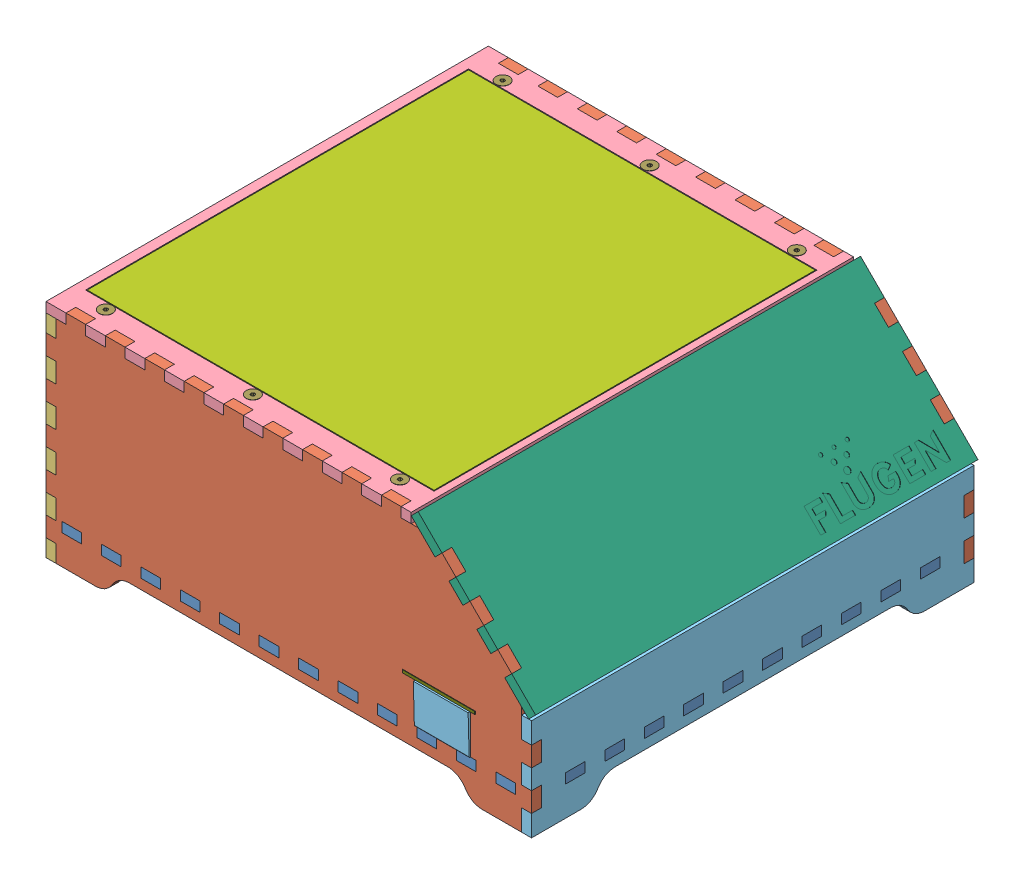
SolidWorks assembly Box assembly R3, configuration Default. Lengths in mm.
Overall size (283.8 130.94 257.74).
91 component instances, 32 part files, 72 mates.
Components (placement in the parent):
- Base 1.3-1: Base 1.3 [Default] at (-719.69 -41.4282 -151.4157) x (1 0 0) z (0 -1 0) size (281.43 256.43 5.71)
- Side panel 1.3-1: Side panel 1.3 [Default] at (-151.1145 -87.4893 122.5004) size (281.43 128.58 5.71)
- Side panel 1.3-2: Side panel 1.3 [Default] at (-151.116 -87.4893 -128.2154) size (281.43 128.58 5.71)
- Backplate 1.3-1: Backplate 1.3 [Default] at (-134.9997 1297.1843 -151.4157) x (0 -1 0) z (-1 0 0) size (122.86 256.43 5.72)
- Top 1.3-1: Top 1.3 [Default] at (1095.0385 64.2887 151.4157) x (-1 0 0) z (0 -1 0) size (211.67 256.43 5.71)
- Front-1: Front [Default] at (140.7147 -927.5509 151.4157) x (0 1 0) z (-1 0 0) size (58.82 256.43 5.71)
- Panel 1.3-1: Panel 1.3 [Default] at (-579.0317 720.6839 -151.4157) x (0.707107 -0.707107 0) z (-0.707107 -0.707107 0) size (96.28 256.43 5.71)
- Peltier assembly-1: Peltier assembly [Default] at (-209.5588 163.9846 -91.398) x (0 0 1) z (1 0 0) size (238 60.94 201)
  - Cold plate-1: Cold plate [Default] at (91.398 99.6959 175.559) size (221 3 201)
  - Heatsink-1: Heatsink [Default] at (31.898 106.6959 75.309) size (119 27.24 200.5)
  - Heatsink-2: Heatsink [Default] at (150.898 106.6959 75.309) size (119 27.24 200.5)
  - 92mm Fan Guard-1: 92mm Fan Guard [Default] at (32.0916 156.652 125.8154) x (0.999999 0 0.001368) z (-0.001368 0 0.999999) size (90.49 4.78 90.49)
  - F9-1: F9 [Default] at (64.0963 125.1552 120.7546) size (93.27 26.59 93.52)
    - F9.STEP-1: F9.STEP [Default] at origin size (93.27 26.59 93.52)
      - F9 body.STEP-1: F9 body.STEP [Default] at (-78.1983 5.7094 50.7544) size (92.01 26.59 92.01)
      - F9 fan.STEP-1: F9 fan.STEP [Default] at (-74.2115 10.4094 -44.9134) x (-0.083202 0 0.996533) z (-0.996533 0 -0.083202) size (86.63 20 86.36)
  - F9-2: F9 [Default] at (64.0963 125.1552 220.8546) size (93.27 26.59 93.52)
    - F9.STEP-1: F9.STEP [Default] at origin size (93.27 26.59 93.52)
      - F9 body.STEP-1: F9 body.STEP [Default] at (-78.1983 5.7094 50.7544) size (92.01 26.59 92.01)
      - F9 fan.STEP-1: F9 fan.STEP [Default] at (-74.2115 10.4094 -44.9134) x (-0.083202 0 0.996533) z (-0.996533 0 -0.083202) size (86.63 20 86.36)
  - F9-3: F9 [Default] at (183.0963 125.1552 120.7546) size (93.27 26.59 93.52)
    - F9.STEP-1: F9.STEP [Default] at origin size (93.27 26.59 93.52)
      - F9 body.STEP-1: F9 body.STEP [Default] at (-78.1983 5.7094 50.7544) size (92.01 26.59 92.01)
      - F9 fan.STEP-1: F9 fan.STEP [Default] at (-74.2115 10.4094 -44.9134) x (-0.083202 0 0.996533) z (-0.996533 0 -0.083202) size (86.63 20 86.36)
  - F9-4: F9 [Default] at (183.0963 125.1552 220.8546) size (93.27 26.59 93.52)
    - F9.STEP-1: F9.STEP [Default] at origin size (93.27 26.59 93.52)
      - F9 body.STEP-1: F9 body.STEP [Default] at (-78.1983 5.7094 50.7544) size (92.01 26.59 92.01)
      - F9 fan.STEP-1: F9 fan.STEP [Default] at (-74.2115 10.4094 -44.9134) x (-0.083202 0 0.996533) z (-0.996533 0 -0.083202) size (86.63 20 86.36)
  - 92mm Fan Guard-3: 92mm Fan Guard [Default] at (151.148 156.652 225.859) size (90.49 4.78 90.49)
  - 92mm Fan Guard-4: 92mm Fan Guard [Default] at (150.6091 156.652 125.7201) x (1 0 0.000944) z (-0.000944 0 1) size (90.49 4.78 90.49)
  - 92mm Fan Guard-5: 92mm Fan Guard [Default] at (32.2135 156.652 225.7935) x (0.999999 0 -0.001588) z (0.001588 0 0.999999) size (90.49 4.78 90.49)
- Case attachment screws-1: Case attachment screws [91253A153] at (51.2503 64.4119 -115) x (0.866025 0 -0.5) z (0 1 0) size (7.8 7.8 25.86)
- Case attachment screws-2: Case attachment screws [91253A153] at (51.2503 64.4119 115) x (0.866025 0 0.5) z (0 1 0) size (7.8 7.8 25.86)
- Case attachment screws-3: Case attachment screws [91253A153] at (-33.9997 64.4119 -115) x (0.866025 0 0.5) z (0 1 0) size (7.8 7.8 25.86)
- Case attachment screws-4: Case attachment screws [91253A153] at (-119.2497 64.4119 -115) x (0.866025 0 -0.5) z (0 1 0) size (7.8 7.8 25.86)
- Case attachment screws-5: Case attachment screws [91253A153] at (-33.9997 64.4119 115) x (0.866025 0 0.5) z (0 1 0) size (7.8 7.8 25.86)
- Case attachment screws-6: Case attachment screws [91253A153] at (-119.2497 64.4119 115) x (0.866025 0 0.5) z (0 1 0) size (7.8 7.8 25.86)
- Cold plate spacer-1: Cold plate spacer [92510A445] at (-119.2497 52.2216 -115) x (1 0 0) z (0 1 0) size (6.35 6.35 12.7)
- Cold plate spacer-2: Cold plate spacer [92510A445] at (-33.9997 52.2216 -115) x (1 0 0) z (0 1 0) size (6.35 6.35 12.7)
- Cold plate spacer-3: Cold plate spacer [92510A445] at (51.2503 52.2216 -115) x (1 0 0) z (0 1 0) size (6.35 6.35 12.7)
- Cold plate spacer-4: Cold plate spacer [92510A445] at (51.2503 52.2216 115) x (1 0 0) z (0 1 0) size (6.35 6.35 12.7)
- Cold plate spacer-5: Cold plate spacer [92510A445] at (-119.2497 52.2216 115) x (1 0 0) z (0 1 0) size (6.35 6.35 12.7)
- Cold plate spacer-6: Cold plate spacer [92510A445] at (-33.9997 52.2216 115) x (1 0 0) z (0 1 0) size (6.35 6.35 12.7)
- Cold plate nut-1: Cold plate nut [90631A007] at (-33.9997 45.3014 115) x (-1 0 0) z (0 0 1) size (7.94 4.48 9.17)
- Cold plate nut-2: Cold plate nut [90631A007] at (-33.9997 45.3014 -115) x (0.5 0 -0.866025) z (-0.866025 0 -0.5) size (7.94 4.48 9.17)
- Cold plate nut-3: Cold plate nut [90631A007] at (51.2503 45.3014 -115) x (0.5 0 -0.866025) z (-0.866025 0 -0.5) size (7.94 4.48 9.17)
- Cold plate nut-4: Cold plate nut [90631A007] at (51.2503 45.3014 115) x (-0.5 0 -0.866025) z (-0.866025 0 0.5) size (7.94 4.48 9.17)
- Cold plate nut-5: Cold plate nut [90631A007] at (-119.2497 45.3014 -115) x (0.5 0 -0.866025) z (-0.866025 0 -0.5) size (7.94 4.48 9.17)
- Cold plate nut-6: Cold plate nut [90631A007] at (-119.2497 45.3014 115) x (-1 0 0) z (0 0 1) size (7.94 4.48 9.17)
- BTS7960 H-Bridge Module-1: BTS7960 H-Bridge Module [Default] at (86.9947 -18.5282 52.2747) x (0 0 -1) z (0 1 0) size (51.5 49.9 42)
  - BTS7960 H-Bridge Module.step-1: BTS7960 H-Bridge Module.step [Default] at origin size (51.5 49.9 42)
    - 2Pos Terminal Block_001.step-1: 2Pos Terminal Block_001.step [Default] at (0.8 20 1.6) x (0 1 0) z (0 0 1) size (10 10.4 16.75)
    - Body_001.step-1: Body_001.step [Default] at origin size (49.5 49.8 1.6)
    - 2Pos Terminal Block_002.step-1: 2Pos Terminal Block_002.step [Default] at (10.7 20 1.6) x (0 1 0) z (0 0 1) size (10 10.4 16.75)
    - Capacitor_001.step-1: Capacitor_001.step [Default] at (-10.7672 19.837 1.6) x (0 -1 0) z (-1 0 0) size (10.12 17.5 10.12)
    - BTN7960_001.step-1: BTN7960_001.step [Default] at (5.9321 -1.893 1.6) size (10 15.38 4.4)
    - BTN7960_002.step-1: BTN7960_002.step [Default] at (-5.9827 -1.8968 1.6) size (10 15.38 4.4)
    - SOJ 20_001.step-1: SOJ 20_001.step [Default] at (17.2939 -12.0721 1.6) x (0 -1 0) z (0 0 1) size (10.85 12.9 2.4)
    - 2x4 Male Header_001.step-1: 2x4 Male Header_001.step [Default] at (5.8669 -22.8725 1.6) size (10.16 5.08 11.3)
    - Fillet.step-1: Fillet.step [Default] at origin size (51.5 31.77 22.9)
    - M2.5x6-Screw.step-1: M2.5x6-Screw.step [Default] at (-13.3 -2.4 2) size (4.5 4.5 6)
    - M2.5x6-Screw.step-2: M2.5x6-Screw.step [Default] at (13.7 -2.4 2) size (4.5 4.5 6)
    - 0805 Resistor_001.step-1: 0805 Resistor_001.step [Default] at (9.9588 -15.7217 1.6) x (0 -1 0) z (0 0 1) size (2 1.25 0.5)
    - 0805 Resistor_002.step-1: 0805 Resistor_002.step [Default] at (7.9588 -15.7217 1.6) x (0 -1 0) z (0 0 1) size (2 1.25 0.5)
    - 0805 Resistor_003.step-1: 0805 Resistor_003.step [Default] at (5.9588 -15.7217 1.6) x (0 -1 0) z (0 0 1) size (2 1.25 0.5)
    - 0805 Resistor_004.step-1: 0805 Resistor_004.step [Default] at (3.9588 -15.7217 1.6) x (0 -1 0) z (0 0 1) size (2 1.25 0.5)
    - 0805 Resistor_005.step-1: 0805 Resistor_005.step [Default] at (1.9588 -15.7217 1.6) x (0 -1 0) z (0 0 1) size (2 1.25 0.5)
    - 0805 Resistor_006.step-1: 0805 Resistor_006.step [Default] at (-0.0412 -15.7217 1.6) x (0 -1 0) z (0 0 1) size (2 1.25 0.5)
    - 0805 Resistor_007.step-1: 0805 Resistor_007.step [Default] at (-2.0412 -15.7217 1.6) x (0 -1 0) z (0 0 1) size (2 1.25 0.5)
    - 0805 Resistor_008.step-1: 0805 Resistor_008.step [Default] at (-4.0412 -15.7217 1.6) x (0 -1 0) z (0 0 1) size (2 1.25 0.5)
- BTS7960 H-Bridge Module-2: BTS7960 H-Bridge Module [Default] at (86.9947 -18.5282 103.7747) x (0 0 -1) z (0 1 0) size (51.5 49.9 42)
  - BTS7960 H-Bridge Module.step-1: BTS7960 H-Bridge Module.step [Default] at origin size (51.5 49.9 42)
    - 2Pos Terminal Block_001.step-1: 2Pos Terminal Block_001.step [Default] at (0.8 20 1.6) x (0 1 0) z (0 0 1) size (10 10.4 16.75)
    - Body_001.step-1: Body_001.step [Default] at origin size (49.5 49.8 1.6)
    - 2Pos Terminal Block_002.step-1: 2Pos Terminal Block_002.step [Default] at (10.7 20 1.6) x (0 1 0) z (0 0 1) size (10 10.4 16.75)
    - Capacitor_001.step-1: Capacitor_001.step [Default] at (-10.7672 19.837 1.6) x (0 -1 0) z (-1 0 0) size (10.12 17.5 10.12)
    - BTN7960_001.step-1: BTN7960_001.step [Default] at (5.9321 -1.893 1.6) size (10 15.38 4.4)
    - BTN7960_002.step-1: BTN7960_002.step [Default] at (-5.9827 -1.8968 1.6) size (10 15.38 4.4)
    - SOJ 20_001.step-1: SOJ 20_001.step [Default] at (17.2939 -12.0721 1.6) x (0 -1 0) z (0 0 1) size (10.85 12.9 2.4)
    - 2x4 Male Header_001.step-1: 2x4 Male Header_001.step [Default] at (5.8669 -22.8725 1.6) size (10.16 5.08 11.3)
    - Fillet.step-1: Fillet.step [Default] at origin size (51.5 31.77 22.9)
    - M2.5x6-Screw.step-1: M2.5x6-Screw.step [Default] at (-13.3 -2.4 2) size (4.5 4.5 6)
    - M2.5x6-Screw.step-2: M2.5x6-Screw.step [Default] at (13.7 -2.4 2) size (4.5 4.5 6)
    - 0805 Resistor_001.step-1: 0805 Resistor_001.step [Default] at (9.9588 -15.7217 1.6) x (0 -1 0) z (0 0 1) size (2 1.25 0.5)
    - 0805 Resistor_002.step-1: 0805 Resistor_002.step [Default] at (7.9588 -15.7217 1.6) x (0 -1 0) z (0 0 1) size (2 1.25 0.5)
    - 0805 Resistor_003.step-1: 0805 Resistor_003.step [Default] at (5.9588 -15.7217 1.6) x (0 -1 0) z (0 0 1) size (2 1.25 0.5)
    - 0805 Resistor_004.step-1: 0805 Resistor_004.step [Default] at (3.9588 -15.7217 1.6) x (0 -1 0) z (0 0 1) size (2 1.25 0.5)
    - 0805 Resistor_005.step-1: 0805 Resistor_005.step [Default] at (1.9588 -15.7217 1.6) x (0 -1 0) z (0 0 1) size (2 1.25 0.5)
    - 0805 Resistor_006.step-1: 0805 Resistor_006.step [Default] at (-0.0412 -15.7217 1.6) x (0 -1 0) z (0 0 1) size (2 1.25 0.5)
    - 0805 Resistor_007.step-1: 0805 Resistor_007.step [Default] at (-2.0412 -15.7217 1.6) x (0 -1 0) z (0 0 1) size (2 1.25 0.5)
    - 0805 Resistor_008.step-1: 0805 Resistor_008.step [Default] at (-4.0412 -15.7217 1.6) x (0 -1 0) z (0 0 1) size (2 1.25 0.5)
Mates (geometry in assembly coordinates):
- Coincident1: coincident anti-aligned: plane of Base 1.3-1 through (-719.69 -47.1432 -151.4157) normal (0 -1 0); plane of Side panel 1.3-1 through (-125.7297 -47.1432 128.2154) normal (0 1 0)
- Coincident2: coincident aligned: plane of Base 1.3-1 through (-134.9997 -47.1432 122.5004) normal (-1 0 0); plane of Side panel 1.3-1 through (-134.9997 -31.4335 128.2154) normal (-1 0 0)
- Coincident3: coincident anti-aligned: plane of Base 1.3-1 through (-108.5837 -47.1432 122.5004) normal (0 0 1); plane of Side panel 1.3-1 through (-151.1145 -87.4893 122.5004) normal (0 0 -1)
- Coincident4: coincident anti-aligned: plane of Base 1.3-1 through (108.5863 -47.1432 -122.5004) normal (0 0 -1); plane of Side panel 1.3-2 through (-151.116 -87.4893 -122.5004) normal (0 0 1)
- Coincident5: coincident anti-aligned: plane of Base 1.3-1 through (-719.69 -47.1432 -151.4157) normal (0 -1 0); plane of Side panel 1.3-2 through (102.8687 -47.1432 -122.5004) normal (0 1 0)
- Coincident6: coincident aligned: plane of Base 1.3-1 through (134.9997 -47.1432 -122.5004) normal (1 0 0); plane of Side panel 1.3-2 through (134.9997 -40.5946 -122.5004) normal (1 0 0)
- Coincident7: coincident anti-aligned: plane of Base 1.3-1 through (-134.9997 -47.1432 -17.1453) normal (-1 0 0); plane of Backplate 1.3-1 through (-134.9997 1297.1843 -151.4157) normal (1 0 0)
- Coincident8: coincident aligned: plane of Side panel 1.3-1 through (-112.1397 -64.2887 128.2154) normal (0 -1 0); plane of Backplate 1.3-1 through (-140.7147 -64.2887 99.6394) normal (0 -1 0)
- Coincident9: coincident anti-aligned: plane of Side panel 1.3-1 through (-151.1145 -87.4893 122.5004) normal (0 0 -1); plane of Backplate 1.3-1 through (-140.7147 -54.2938 122.5004) normal (0 0 1)
- Coincident11: coincident aligned: plane of Backplate 1.3-1 through (-140.7147 1297.1843 -151.4157) normal (-1 0 0); plane of Top 1.3-1 through (-140.7147 58.5737 128.2151) normal (-1 0 0)
- Coincident12: coincident anti-aligned: plane of Backplate 1.3-1 through (-140.7147 58.5737 128.2154) normal (0 1 0); plane of Top 1.3-1 through (1095.0385 58.5737 151.4157) normal (0 -1 0)
- Coincident13: coincident anti-aligned: plane of Side panel 1.3-1 through (-151.1145 -87.4893 122.5004) normal (0 0 -1); plane of Top 1.3-1 through (-117.7455 58.5737 122.5004) normal (0 0 1)
- Coincident14: coincident anti-aligned: plane of Base 1.3-1 through (134.9997 -47.1432 108.5837) normal (1 0 0); plane of Front-1 through (134.9997 -927.5509 151.4157) normal (-1 0 0)
- Coincident15: coincident anti-aligned: plane of Side panel 1.3-1 through (-151.1145 -87.4893 122.5004) normal (0 0 -1); plane of Front-1 through (134.9997 -29.163 122.5004) normal (0 0 1)
- Coincident16: coincident aligned: plane of Side panel 1.3-1 through (112.1413 -64.2887 128.2154) normal (0 -1 0); plane of Front-1 through (134.9997 -64.2887 98.9002) normal (0 -1 0)
- Coincident17: coincident anti-aligned: plane of Side panel 1.3-1 through (117.1222 16.4477 128.2154) normal (0.707107 0.707107 0); plane of Panel 1.3-1 through (-583.0728 716.6428 -151.4157) normal (-0.707107 -0.707107 0)
- Coincident18: coincident aligned: plane of Side panel 1.3-1 through (-151.1145 -87.4893 128.2154) normal (0 0 1); plane of Panel 1.3-1 through (84.7942 48.7757 128.2154) normal (0 0 1)
- Coincident21: coincident: plane of Side panel 1.3-1 through (125.207 8.3657 128.2154) normal (0.707151 -0.707062 0); line of Panel 1.3-1 through (129.2465 12.4057 128.2154) axis (0 0 -1)
- Coincident22: coincident aligned: plane of Top 1.3-1 through (1095.0385 64.2887 151.4157) normal (0 1 0); plane of Peltier assembly-1/Cold plate-1 through (-33.9997 64.2887 0) normal (0 1 0)
- Width1: width anti-aligned: plane of Peltier assembly-1/Cold plate-1 through (66.5003 61.2887 -110.5) normal (0 0 -1); plane of Peltier assembly-1/Cold plate-1 through (66.5003 61.2887 110.5) normal (0 0 1); plane of Side panel 1.3-1 through (-151.1145 -87.4893 128.2154) normal (0 0 1); plane of Side panel 1.3-2 through (-151.116 -87.4893 -128.2154) normal (0 0 -1)
- Distance1: distance = 0.5 mm anti-aligned: plane of Backplate 1.3-1 through (-134.9997 1297.1843 -151.4157) normal (1 0 0); plane of Peltier assembly-1/Cold plate-1 through (-134.4997 61.2887 -110.5) normal (-1 0 0)
- Parallel3: parallel aligned: plane of Peltier assembly-1/Cold plate-1 through (66.5003 61.2887 -110.5) normal (0 0 -1); plane of Case attachment screws-4 through (-119.8226 62.6872 -114.0078) normal (0 0 -1)
- Parallel4: parallel aligned: plane of Peltier assembly-1/Cold plate-1 through (66.5003 61.2887 -110.5) normal (0 0 -1); plane of Case attachment screws-3 through (-34.5726 62.6872 -114.0078) normal (0 0 -1)
- Parallel5: parallel aligned: plane of Peltier assembly-1/Cold plate-1 through (66.5003 61.2887 -110.5) normal (0 0 -1); plane of Case attachment screws-1 through (50.6774 62.6872 -114.0078) normal (0 0 -1)
- Parallel6: parallel aligned: plane of Peltier assembly-1/Cold plate-1 through (66.5003 61.2887 110.5) normal (0 0 1); plane of Case attachment screws-2 through (51.8231 62.6872 114.0078) normal (0 0 1)
- Parallel7: parallel aligned: plane of Peltier assembly-1/Cold plate-1 through (66.5003 61.2887 110.5) normal (0 0 1); plane of Case attachment screws-5 through (-33.4269 62.6872 114.0078) normal (0 0 1)
- Parallel8: parallel aligned: plane of Peltier assembly-1/Cold plate-1 through (66.5003 61.2887 110.5) normal (0 0 1); plane of Case attachment screws-6 through (-118.6769 62.6872 114.0078) normal (0 0 1)
- Concentric3: concentric anti-aligned: circle of Case attachment screws-6; cylinder of Cold plate spacer-5 through (-119.2497 58.5716 115) axis (0 -1 0) radius 3.175
- Coincident38: coincident: line of Side panel 1.3-1 through (-129.1761 58.5716 122.5004) axis (-1 0 0); plane of Cold plate spacer-5 through (-119.2497 58.5716 115) normal (0 1 0)
- Concentric4: concentric anti-aligned: circle of Case attachment screws-5; cylinder of Cold plate spacer-6 through (-33.9997 58.5716 115) axis (0 -1 0) radius 1.778
- Coincident39: coincident: line of Side panel 1.3-1 through (-37.735 58.5716 128.2154) axis (0 0 -1); plane of Cold plate spacer-6 through (-33.9997 58.5716 115) normal (0 1 0)
- Concentric5: concentric anti-aligned: circle of Case attachment screws-2; cylinder of Cold plate spacer-4 through (51.2503 58.5716 115) axis (0 -1 0) radius 1.778
- Coincident40: coincident: line of Side panel 1.3-1 through (42.274 58.5716 128.2154) axis (0 0 -1); plane of Cold plate spacer-4 through (51.2503 58.5716 115) normal (0 1 0)
- Concentric6: concentric anti-aligned: circle of Case attachment screws-4; cylinder of Cold plate spacer-1 through (-119.2497 58.5716 -115) axis (0 -1 0) radius 1.778
- Coincident41: coincident: line of Side panel 1.3-2 through (-117.7468 58.5716 -122.5004) axis (0 0 -1); plane of Cold plate spacer-1 through (-119.2497 58.5716 -115) normal (0 1 0)
- Concentric7: concentric anti-aligned: circle of Case attachment screws-3; cylinder of Cold plate spacer-2 through (-33.9997 58.5716 -115) axis (0 -1 0) radius 1.778
- Coincident42: coincident: line of Side panel 1.3-2 through (-37.7365 58.5716 -122.5004) axis (0 0 -1); plane of Cold plate spacer-2 through (-33.9997 58.5716 -115) normal (0 1 0)
- Concentric8: concentric anti-aligned: circle of Case attachment screws-1; cylinder of Cold plate spacer-3 through (51.2503 58.5716 -115) axis (0 -1 0) radius 1.778
- Coincident43: coincident: line of Side panel 1.3-2 through (53.7032 58.5716 -122.5004) axis (0 0 -1); plane of Cold plate spacer-3 through (51.2503 58.5716 -115) normal (0 1 0)
- Concentric9: concentric aligned: circle of Case attachment screws-6; cylinder of Cold plate nut-6 through (-119.2497 39.6658 115) axis (0 1 0) radius 2.3257
- Coincident47: coincident: line of Peltier assembly-1/Heatsink-2 through (66.2503 45.3014 118.5174) axis (-1 0 0); plane of Cold plate nut-6 through (-115.281 45.3014 108.1259) normal (0 1 0)
- Parallel12: parallel aligned: plane of Peltier assembly-1/Heatsink-2 through (-134.2497 45.8011 0.5) normal (-1 0 0); plane of Cold plate nut-6 through (-123.2185 40.9358 117.2914) normal (-1 0 0)
- Concentric10: concentric aligned: cylinder of Case attachment screws-5 through (-33.9997 64.4119 115) axis (0 1 0) radius 3.8989; cylinder of Cold plate nut-1 through (-33.9997 39.6658 115) axis (0 1 0) radius 2.3257
- Coincident51: coincident: line of Peltier assembly-1/Heatsink-2 through (66.2503 45.3014 118.5174) axis (-1 0 0); plane of Cold plate nut-1 through (-30.031 45.3014 108.1259) normal (0 1 0)
- Parallel13: parallel aligned: plane of Peltier assembly-1/Heatsink-2 through (-134.2497 45.8011 0.5) normal (-1 0 0); plane of Cold plate nut-1 through (-37.9685 40.9358 117.2914) normal (-1 0 0)
- Concentric11: concentric aligned: circle of Case attachment screws-2; cylinder of Cold plate nut-4 through (51.2503 39.6658 115) axis (0 1 0) radius 2.3257
- Coincident53: coincident: line of Peltier assembly-1/Heatsink-2 through (66.2503 45.3014 118.5174) axis (-1 0 0); plane of Cold plate nut-4 through (59.1878 45.3014 115) normal (0 1 0)
- Parallel14: parallel aligned: plane of Peltier assembly-1/Heatsink-2 through (-134.2497 45.8011 0.5) normal (-1 0 0); plane of Cold plate nut-4 through (47.2815 40.9358 117.2914) normal (-1 0 0)
- Concentric12: concentric aligned: circle of Case attachment screws-4; cylinder of Cold plate nut-5 through (-119.2497 39.6658 -115) axis (0 1 0) radius 2.3257
- Coincident55: coincident: line of Peltier assembly-1/Heatsink-1 through (66.2503 45.3014 -118.5174) axis (-1 0 0); plane of Cold plate nut-5 through (-115.281 45.3014 -108.1259) normal (0 1 0)
- Parallel15: parallel anti-aligned: plane of Peltier assembly-1/Heatsink-1 through (-134.2497 45.8011 -118.5) normal (-1 0 0); plane of Cold plate nut-5 through (-115.281 40.9358 -117.2914) normal (1 0 0)
- Concentric13: concentric aligned: circle of Case attachment screws-3; cylinder of Cold plate nut-2 through (-33.9997 39.6658 -115) axis (0 1 0) radius 2.3257
- Coincident57: coincident: line of Peltier assembly-1/Heatsink-1 through (66.2503 45.3014 -118.5174) axis (-1 0 0); plane of Cold plate nut-2 through (-30.031 45.3014 -108.1259) normal (0 1 0)
- Parallel16: parallel anti-aligned: plane of Peltier assembly-1/Heatsink-1 through (-134.2497 45.8011 -118.5) normal (-1 0 0); plane of Cold plate nut-2 through (-30.031 40.9358 -117.2914) normal (1 0 0)
- Concentric14: concentric aligned: circle of Case attachment screws-1; cylinder of Cold plate nut-3 through (51.2503 39.6658 -115) axis (0 1 0) radius 2.3257
- Coincident59: coincident: line of Peltier assembly-1/Heatsink-1 through (66.2503 45.3014 -118.5174) axis (-1 0 0); plane of Cold plate nut-3 through (55.219 45.3014 -108.1259) normal (0 1 0)
- Parallel17: parallel anti-aligned: plane of Peltier assembly-1/Heatsink-1 through (-134.2497 45.8011 -118.5) normal (-1 0 0); plane of Cold plate nut-3 through (55.219 40.9358 -117.2914) normal (1 0 0)
- Symmetric1: symmetric aligned: plane of Side panel 1.3-1 through (-151.1145 -87.4893 128.2154) normal (0 0 1); plane of Side panel 1.3-2 through (-151.116 -87.4893 -128.2154) normal (0 0 -1)
- Symmetric2: symmetric aligned: plane of Backplate 1.3-1 through (-140.7147 1297.1843 -151.4157) normal (-1 0 0); plane of Front-1 through (140.7147 -927.5509 151.4157) normal (1 0 0)
- Symmetric3: symmetric aligned: plane of Backplate 1.3-1 through (-140.7147 -64.2887 99.6394) normal (0 -1 0); plane of Top 1.3-1 through (1095.0385 64.2887 151.4157) normal (0 1 0)
- Coincident62: coincident aligned: cone of Top 1.3-1 through (51.2503 64.2887 115) axis (0 -1 0); cone of Case attachment screws-2 through (51.2503 61.9481 115) axis (0 -1 0)
- Coincident63: coincident aligned: cone of Top 1.3-1 through (-33.9997 64.2887 115) axis (0 -1 0); cone of Case attachment screws-5 through (-33.9997 61.9481 115) axis (0 -1 0)
- Coincident65: coincident aligned: cone of Top 1.3-1 through (-119.2497 64.2887 115) axis (0 -1 0); cone of Case attachment screws-6 through (-119.2497 61.9481 115) axis (0 -1 0)
- Coincident66: coincident aligned: cone of Top 1.3-1 through (-119.2497 64.2887 -115) axis (0 -1 0); cone of Case attachment screws-4 through (-119.2497 61.9481 -115) axis (0 -1 0)
- Coincident67: coincident aligned: cone of Top 1.3-1 through (-33.9997 64.2887 -115) axis (0 -1 0); cone of Case attachment screws-3 through (-33.9997 61.9481 -115) axis (0 -1 0)
- Coincident68: coincident aligned: cone of Top 1.3-1 through (51.2503 64.2887 -115) axis (0 -1 0); cone of Case attachment screws-1 through (51.2503 61.9481 -115) axis (0 -1 0)
- Parallel20: parallel anti-aligned: plane of Base 1.3-1 through (-719.69 -41.4282 -151.4157) normal (0 1 0); plane of BTS7960 H-Bridge Module-2/BTS7960 H-Bridge Module.step-1/Body_001.step-1 through (86.9947 -18.5282 103.7747) normal (0 -1 0)
- Coincident74: coincident aligned: plane of BTS7960 H-Bridge Module-1/BTS7960 H-Bridge Module.step-1/Fillet.step-1 through (105.2797 -18.5282 26.5247) normal (1 0 0); plane of BTS7960 H-Bridge Module-2/BTS7960 H-Bridge Module.step-1/Fillet.step-1 through (105.2797 -18.5282 78.0247) normal (1 0 0)
- Coincident76: coincident aligned: plane of BTS7960 H-Bridge Module-1/BTS7960 H-Bridge Module.step-1/Body_001.step-1 through (86.9947 -16.9282 52.2747) normal (0 1 0); plane of BTS7960 H-Bridge Module-2/BTS7960 H-Bridge Module.step-1/Body_001.step-1 through (86.9947 -16.9282 103.7747) normal (0 1 0)
- Coincident78: coincident: plane of BTS7960 H-Bridge Module-1/BTS7960 H-Bridge Module.step-1/Fillet.step-1 through (105.2797 -18.5282 78.0247) normal (0 -0.026177 0.999657); line of BTS7960 H-Bridge Module-2/BTS7960 H-Bridge Module.step-1/Fillet.step-1 through (73.5097 -18.5282 78.0247) axis (1 0 0)
- Coincident79: coincident anti-aligned: line of Base 1.3-1 through (108.5863 -41.4282 128.2154) axis (-1 0 0); line of BTS7960 H-Bridge Module-2/BTS7960 H-Bridge Module.step-1/Fillet.step-1 through (73.5097 -41.4282 128.2154) axis (1 0 0)
- Coincident80: coincident: plane of Base 1.3-1 through (-719.69 -41.4282 -151.4157) normal (0 1 0); line of BTS7960 H-Bridge Module-2/BTS7960 H-Bridge Module.step-1/Fillet.step-1 through (73.5097 -41.4282 107.2154) axis (1 0 0)
